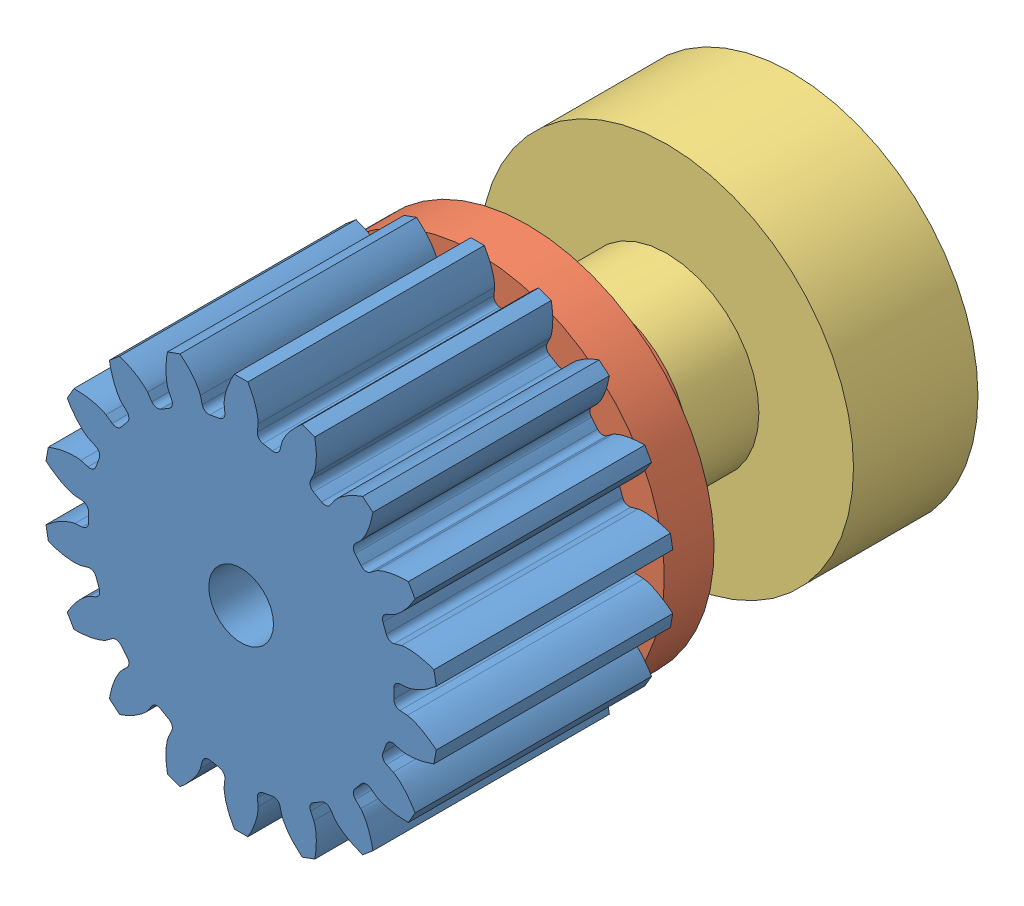
SolidWorks assembly pronation top gears, configuration Default. Lengths in mm.
Overall size (39.82 40.22 56.13).
3 component instances, 3 part files, 6 mates.
Components (placement in the parent):
- 24-18 Pronation Potentiometer Gear-1: 24-18 Pronation Potentiometer Gear [7880K39] at (5.6209 21.4573 41.8559) size (39.82 40.22 24.13)
- bottom gear connection-1: bottom gear connection [Default] at (5.6209 21.4573 23.4409) x (-1 0 0) z (0 -1 0) size (38.1 12.19 38.1)
- top gear connection-1: top gear connection [Default] at (5.6209 21.4573 -8.5631) x (1 0 0) z (0 -1 0) size (38.1 19.81 38.1)
Mates (geometry in assembly coordinates):
- Concentric1: concentric aligned: circle of 24-18 Pronation Potentiometer Gear-1; circle of bottom gear connection-1
- Concentric2: concentric aligned: circle of 24-18 Pronation Potentiometer Gear-1; circle of bottom gear connection-1
- Coincident1: coincident anti-aligned: plane of 24-18 Pronation Potentiometer Gear-1 through (5.6209 21.4573 23.4409) normal (0 0 -1); plane of bottom gear connection-1 through (5.6209 21.4573 23.4409) normal (0 0 1)
- Coincident3: coincident: plane of bottom gear connection-1 through (5.6209 21.4573 11.2489) normal (0 0 -1); plane of top gear connection-1 through (7.2182 31.3597 11.2489) normal (0 0 1)
- Concentric6: concentric: circle of bottom gear connection-1; circle of top gear connection-1
- Concentric7: concentric aligned: circle of bottom gear connection-1; circle of top gear connection-1
